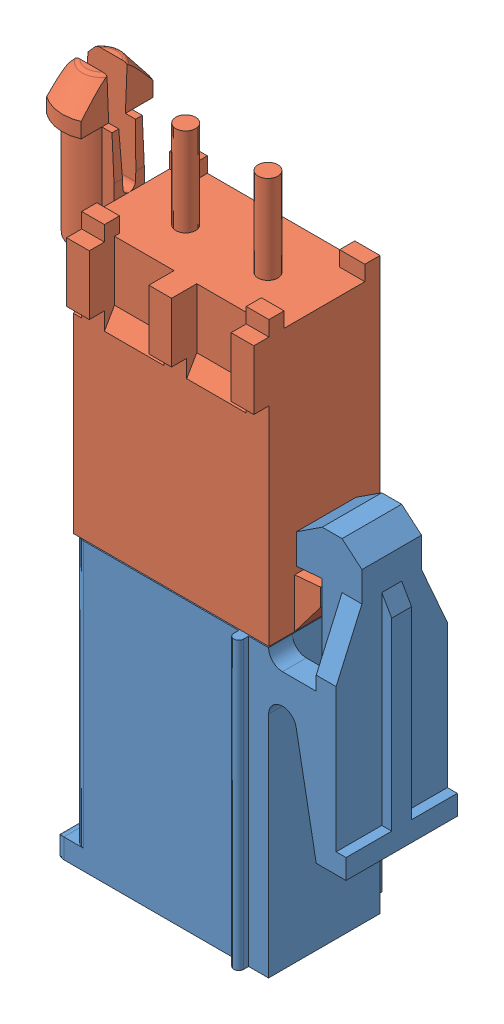
SolidWorks assembly 2p-mate-n-lok-asm, configuration Default. Lengths in mm.
Overall size (16.33 32.99 7.3).
2 component instances, 2 part files, 5 mates.
Components (placement in the parent):
- c-172165-1-h-3d-1: c-172165-1-h-3d [Default] at (-4.8618 -4.9494 -27.7591) x (0 0 1) z (0 1 0) size (7.1 14.7 23.7)
- c-1-770872-0-h-3d-1: c-1-770872-0-h-3d [Default] at (-4.9149 -14.2494 -27.8121) x (-1 0 0) z (0 -1 0) size (13.69 6.35 18.68)
Mates (geometry in assembly coordinates):
- Coincident2: coincident anti-aligned: plane of c-172165-1-h-3d-1 through (1.0668 -14.2494 -28.8129) normal (-1 0 0); plane of c-1-770872-0-h-3d-1 through (1.0668 -4.5626 -25.1858) normal (1 0 0)
- Coincident3: coincident anti-aligned: plane of c-172165-1-h-3d-1 through (3.5168 -14.2494 -28.8129) normal (0 0 -1); plane of c-1-770872-0-h-3d-1 through (1.0155 -4.5626 -28.8129) normal (0 0 1)
- Coincident4: coincident anti-aligned: plane of c-172165-1-h-3d-1 through (-0.0382 -14.2494 -23.2879) normal (0 1 0); plane of c-1-770872-0-h-3d-1 through (-0.1966 -14.2494 -29.9406) normal (0 -1 0)
- Coincident8: coincident aligned: plane of c-1-770872-0-h-3d-1 through (10.0264 0 -24.1291) normal (0 1 0)
- Coincident9: coincident aligned: plane of c-1-770872-0-h-3d-1 through (0 0.285 -24.1291) normal (1 0 0)
